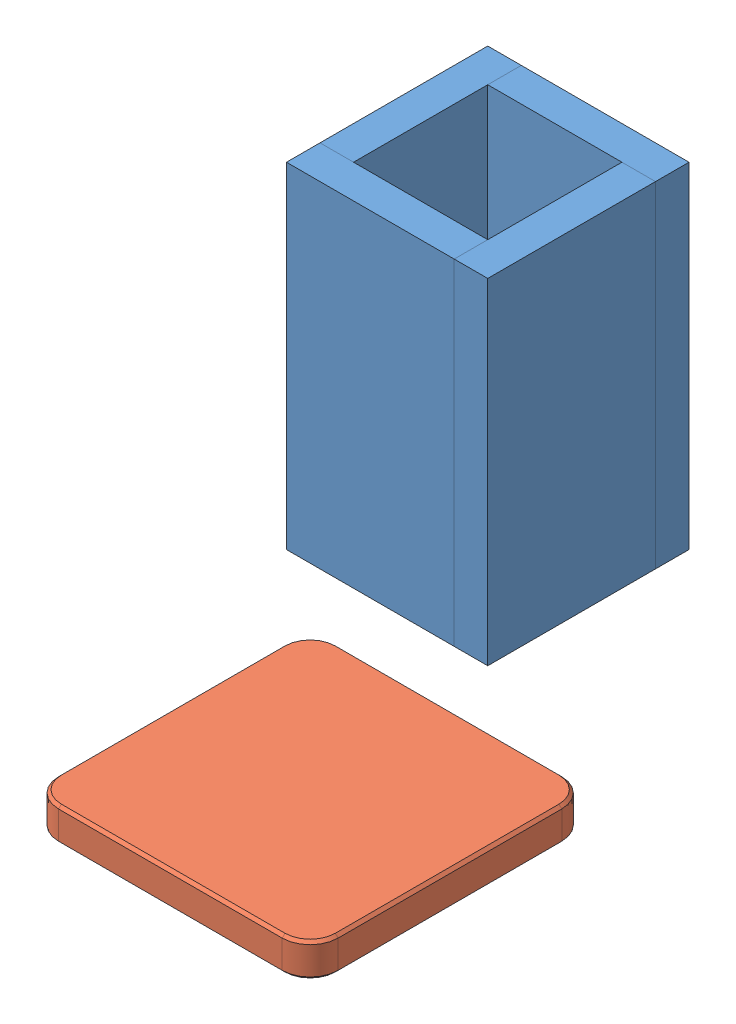
SolidWorks assembly Assem5, configuration Default. Lengths in mm.
Overall size (128.59 132 192.12).
5 component instances, 2 part files, 9 mates.
Components (placement in the parent):
- Part2-1: Part2 [Default] at (13.4944 58.317 105.5511) size (60 120 12)
- Part2-2: Part2 [Default] at (1.4944 58.317 165.5511) size (60 120 12)
- Part2-3: Part2 [Default] at (-16.5056 58.317 135.5511) x (0 0 1) z (-1 0 0) size (60 120 12)
- Part2-4: Part2 [Default] at (43.4944 58.317 147.5511) x (0 0 1) z (-1 0 0) size (60 120 12)
- part 1-1: part 1 [Default] at (50.0877 -1.683 247.6715) x (1 0 0) z (0 -1 0) size (100 100 12)
Mates (geometry in assembly coordinates):
- Coincident2: coincident anti-aligned: plane of Part2-1 through (13.4944 58.317 117.5511) normal (0 0 1); plane of Part2-4 through (31.4944 118.317 117.5511) normal (0 0 -1)
- Coincident3: coincident anti-aligned: line of Part2-1 through (43.4944 -1.683 117.5511) axis (0 1 0); line of Part2-4 through (43.4944 118.317 117.5511) axis (0 -1 0)
- Coincident4: coincident: point of Part2-1; point of Part2-4
- Coincident5: coincident aligned: line of Part2-2 through (31.4944 -1.683 177.5511) axis (0 1 0); line of Part2-4 through (31.4944 -1.683 177.5511) axis (0 1 0)
- Coincident6: coincident: point of Part2-2; point of Part2-4
- Coincident7: coincident anti-aligned: line of Part2-2 through (-28.5056 118.317 165.5511) axis (0 -1 0); line of Part2-3 through (-28.5056 -1.683 165.5511) axis (0 1 0)
- Coincident10: coincident anti-aligned: plane of Part2-1 through (-16.5056 118.317 117.5511) normal (-1 0 0); plane of Part2-3 through (-16.5056 58.317 135.5511) normal (1 0 0)
- Coincident11: coincident: line of Part2-2 through (31.4944 118.317 165.5511) axis (-1 0 0); point of Part2-3
- Coincident18: coincident anti-aligned: plane of Part2-3 through (-28.5056 -1.683 105.5511) normal (0 -1 0); plane of part 1-1 through (50.0877 -1.683 247.6715) normal (0 1 0)
